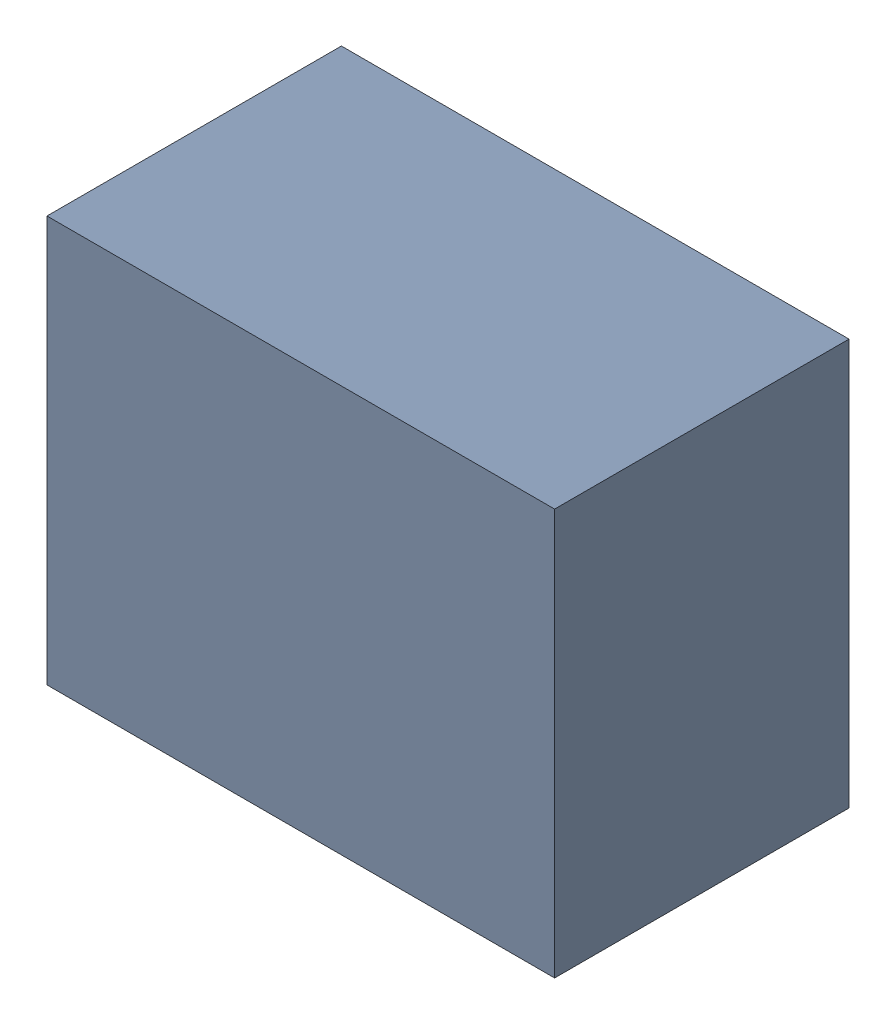
SolidWorks assembly U2, configuration Default. Lengths in mm.
Overall size (1 0.8 0.58).
2 component instances, 1 part files, 0 mates.
Components (placement in the parent):
- 810372112-1: 810372112 [Default] at (112.75 8.15 0.5) size (1 0.8 0.58)
  - Extruded_43-1: Extruded_43 [Default] at origin size (1 0.8 0.58)
